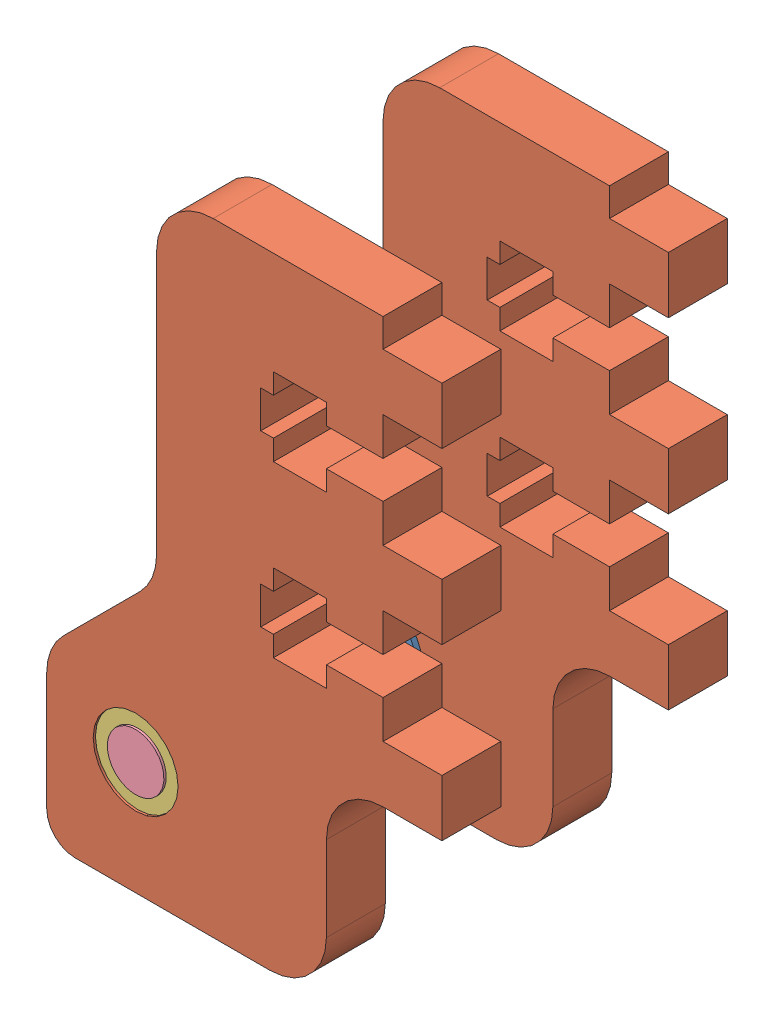
SolidWorks assembly PULLEY BLOCK, LOWER OUTFEED, configuration Default. Lengths in mm.
Overall size (46.41 69.85 32).
6 component instances, 4 part files, 14 mates.
Components (placement in the parent):
- 1375K39-1: 1375K39 [Default] at (-27.7495 -57.15 1.5875) x (0.833721 0.552185 0) z (0.552185 -0.833721 0) size (17.4 14.3 17.4)
- MOUNT OFFSET, PULLY-1: MOUNT OFFSET, PULLY [Default] x (1 0 0) z (0 0 -1) size (44.32 69.85 6.6)
- MOUNT OFFSET, PULLY-2: MOUNT OFFSET, PULLY [Default] at (0 0 25.4) x (1 0 0) z (0 0 -1) size (44.32 69.85 6.6)
- 6338K411-1: 6338K411 [Default] at (-27.7495 -57.15 -6.35) x (-0.837169 -0.546944 0) z (-0.546944 0.837169 0) size (12.7 7.94 12.7)
- 6338K411-2: 6338K411 [Default] at (-27.7495 -57.15 25.146) x (0.871903 0.489679 0) z (-0.489679 0.871903 0) size (12.7 7.94 12.7)
- SHAFT, PULLY-1: SHAFT, PULLY [Default] at (-27.7495 -57.15 25.4) x (0.857168 -0.515036 0) z (0 0 -1) size (6.35 6.35 31.75)
Mates (geometry in assembly coordinates):
- Concentric1: concentric aligned: cylinder of 1375K39-1 through (-27.7495 -57.15 28.2701) axis (0 0 1) radius 3.175; cylinder of MOUNT OFFSET, PULLY-1 through (-27.7495 -57.15 -6.604) axis (0 0 1) radius 4.7625
- Concentric2: concentric aligned: cylinder of MOUNT OFFSET, PULLY-1 through (-27.7495 -57.15 -6.604) axis (0 0 1) radius 4.7625; cylinder of MOUNT OFFSET, PULLY-2 through (-27.7495 -57.15 18.796) axis (0 0 1) radius 4.7625
- Concentric3: concentric aligned: cylinder of MOUNT OFFSET, PULLY-2 through (-27.7495 -57.15 18.796) axis (0 0 1) radius 4.7625; cylinder of 6338K411-2 through (-27.7495 -57.15 25.146) axis (0 0 1) radius 4.7625
- Concentric4: concentric anti-aligned: cylinder of MOUNT OFFSET, PULLY-1 through (-27.7495 -57.15 -6.604) axis (0 0 1) radius 4.7625; cylinder of 6338K411-1 through (-27.7495 -57.15 -6.35) axis (0 0 -1) radius 4.7625
- Coincident3: coincident anti-aligned: plane of MOUNT OFFSET, PULLY-1 through (0 0 0) normal (0 0 1); plane of 6338K411-1 through (-24.2764 -62.466 0) normal (0 0 -1)
- Coincident4: coincident aligned: plane of MOUNT OFFSET, PULLY-1 through (-25.4 0 -6.604) normal (-1 0 0); plane of MOUNT OFFSET, PULLY-2 through (-25.4 0 18.796) normal (-1 0 0)
- Coincident5: coincident anti-aligned: plane of MOUNT OFFSET, PULLY-2 through (0 0 18.796) normal (0 0 -1); plane of 6338K411-2 through (-24.64 -62.6866 18.796) normal (0 0 1)
- Distance1: distance = 25.4 mm aligned: plane of MOUNT OFFSET, PULLY-1 through (0 0 -6.604) normal (0 0 -1); plane of MOUNT OFFSET, PULLY-2 through (0 0 18.796) normal (0 0 -1)
- Concentric5: concentric anti-aligned: cylinder of 6338K411-1 through (-27.7495 -57.15 -6.35) axis (0 0 -1) radius 3.175; cylinder of SHAFT, PULLY-1 through (-27.7495 -57.15 -6.35) axis (0 0 1) radius 3.175
- Coincident8: coincident aligned: plane of MOUNT OFFSET, PULLY-2 through (0 0 25.4) normal (0 0 1); plane of SHAFT, PULLY-1 through (-27.7495 -57.15 25.4) normal (0 0 1)
- Coincident11: coincident anti-aligned: plane of MOUNT OFFSET, PULLY-1 through (0 0 0) normal (0 0 -1); plane of assembly through (0 0 0) normal (0 0 1)
- Coincident12: coincident anti-aligned: plane of MOUNT OFFSET, PULLY-1 through (0 0 0) normal (0 -1 0); plane of assembly through (0 0 0) normal (0 1 0)
- Coincident13: coincident aligned: plane of MOUNT OFFSET, PULLY-1; plane of assembly through (0 0 0) normal (1 0 0)
- Coincident14: coincident anti-aligned: plane of 6338K411-1 through (-26.013 -59.808 1.5875) normal (0 0 1); plane of 1375K39-1 through (-25.1024 -55.3968 1.5875) normal (0 0 -1)
